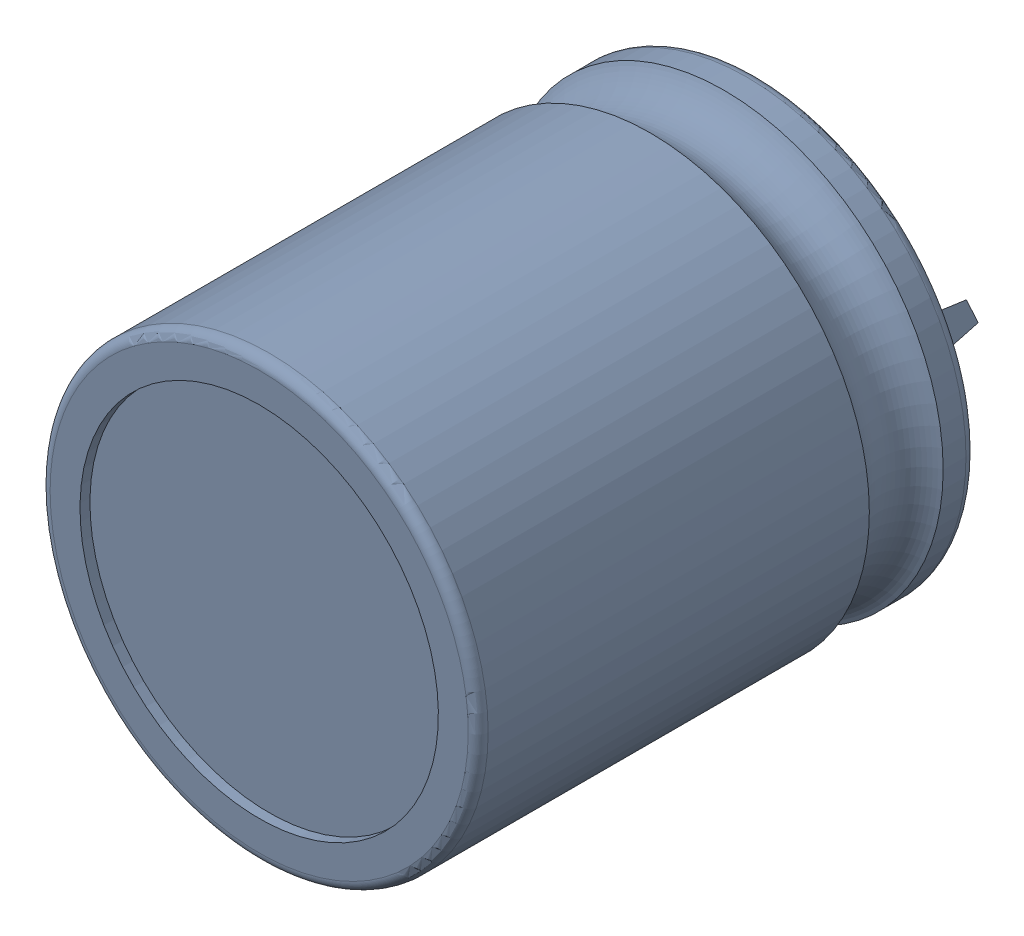
SolidWorks assembly C2, configuration Default. Lengths in mm.
Overall size (22 22 31.01).
4 component instances, 2 part files, 0 mates.
Components (placement in the parent):
- Capacitor22x25-1: Capacitor22x25 [Default] at (131.7171 46.9078 -3.686) x (1 0 0) z (0 -1 0) size (22 31.01 22)
  - User_Library-ECEC2DP271BJ-1: User_Library-ECEC2DP271BJ [Default] at (8.9531 3.6858 17.317) size (22 25.01 22)
  - User_Library-CAP_EL_SNAP-IN_10_35x45_Valor_predeterminado-1: User_Library-CAP_EL_SNAP-IN_10_35x45_Valor_predeterminado [Default] at (14.4607 11.8368 29.4898) x (0.642788 0 0.766044) z (-0.766044 0 0.642788) size (3.5 7.01 5.68)
  - User_Library-CAP_EL_SNAP-IN_10_35x45_Valor_predeterminado-2: User_Library-CAP_EL_SNAP-IN_10_35x45_Valor_predeterminado [Default] at (2.8917 11.8368 4.8301) x (-0.67559 0 -0.737277) z (0.737277 0 -0.67559) size (3.5 7.01 5.68)
